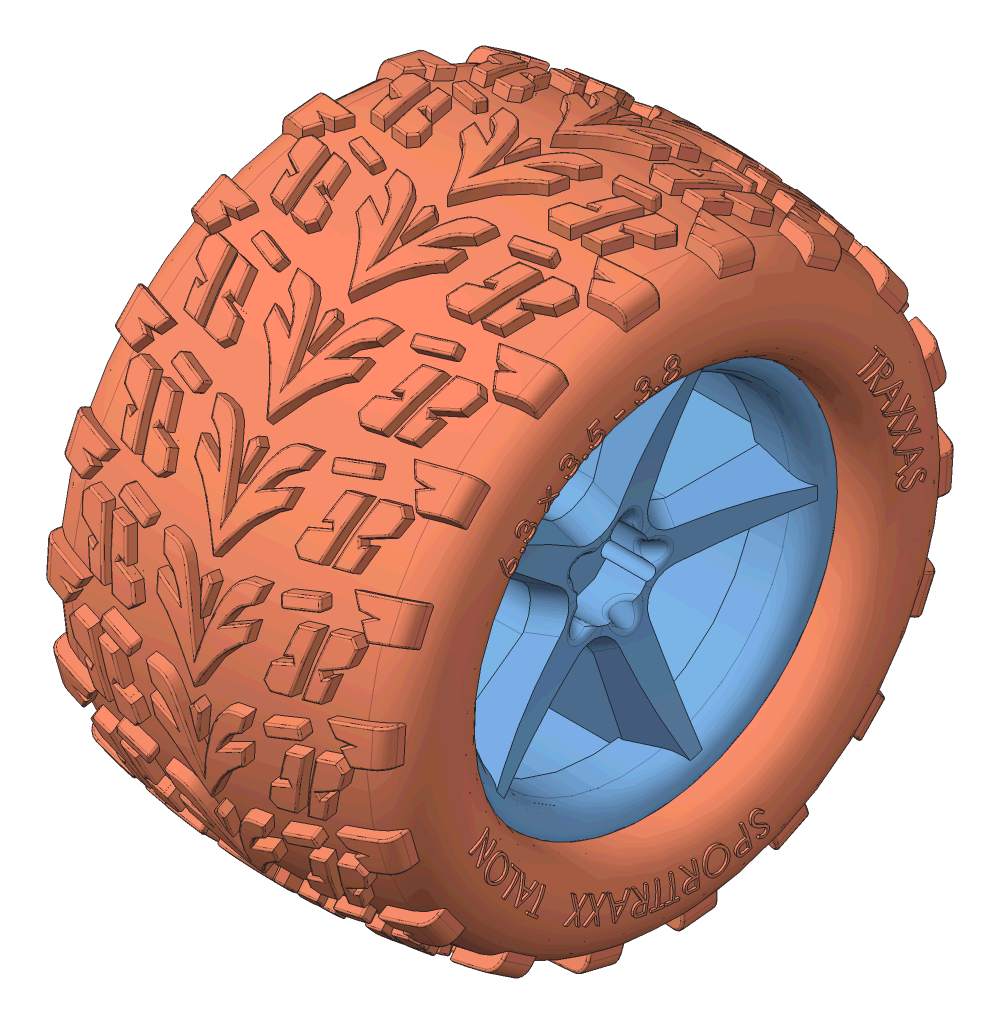
SolidWorks assembly Wheel, configuration Default. Lengths in mm.
Overall size (106.88 166.05 166.47).
2 component instances, 2 part files, 2 mates.
Components (placement in the parent):
- Wheel Rim-1: Wheel Rim [Default] at (-5.7009 62.13 94.8184) size (78.74 101.6 101.6)
- Wheel Tire-1: Wheel Tire [Default] at (-5.7009 62.1295 94.8183) size (106.88 166.05 166.47)
Mates (geometry in assembly coordinates):
- Concentric1: concentric: cylinder of Wheel Rim-1 through (-45.0709 62.13 94.8184) axis (-1 0 0) radius 50.8; cylinder of Wheel Tire-1 through (-45.0732 62.13 94.8184) axis (-1 0 0) radius 50.8
- Coincident1: coincident aligned: plane of Wheel Rim-1 through (-5.7009 62.13 94.8184) normal (1 0 0); plane of Wheel Tire-1 through (-5.7009 62.1295 94.8183) normal (1 0 0)
